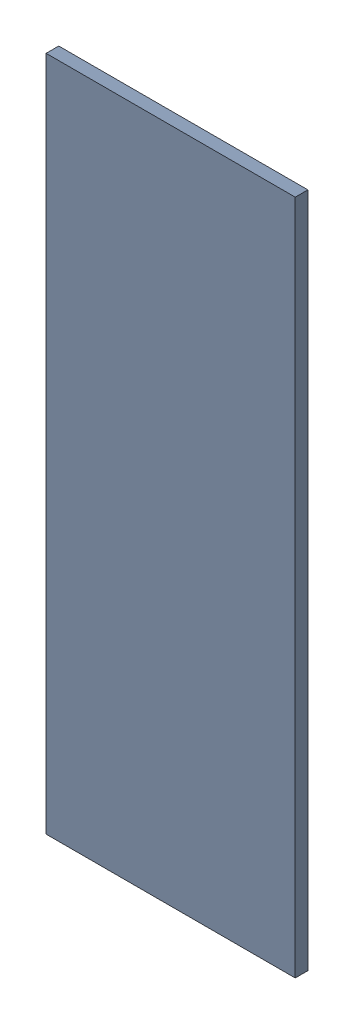
SolidWorks assembly Pad RAK4600-36(24.975mm,31.391mm) on Top Layer, configuration Predeterminado. Lengths in mm.
Overall size (0.7 1.9 0.04).
2 component instances, 1 part files, 0 mates.
Components (placement in the parent):
- Pad RAK4600-36(24.975mm,31.391mm) on Top Layer-1-1: Pad RAK4600-36(24.975mm,31.391mm) on Top Layer-1 [Predeterminado] at (-68.317 -44.187 -0.0457) size (0.7 1.9 0.04)
  - Pad RAK4600-36(24.975mm,31.391mm) on Top Layer-Part-1-1: Pad RAK4600-36(24.975mm,31.391mm) on Top Layer-Part-1 [Predeterminado] at origin size (0.7 1.9 0.04)
